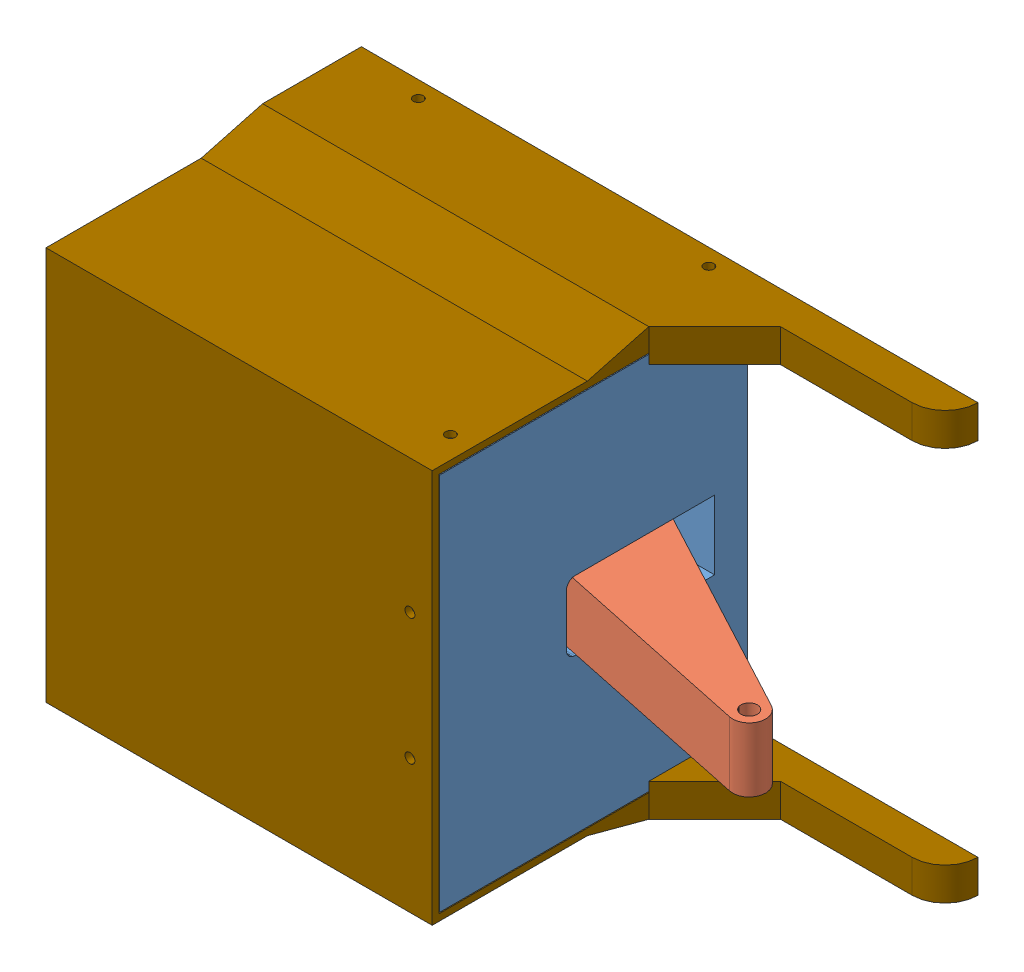
SolidWorks assembly v3, configuration Default. Lengths in mm.
Overall size (187.3 129.6 106.02).
11 component instances, 9 part files, 43 mates.
Components (placement in the parent):
- base-1: base [Default] at origin size (115 115 93.5)
- arm1-1: arm1 [Default] x (1 0 0) z (0 1 0) size (179.32 53.43 32)
- arm2-1: arm2 [Default] x (1 0 0) z (0 1 0) size (87.4 53.4 9.5)
- springBlock-1: springBlock [Default] at (-75 0 0) x (0 0 1) z (-1 0 0) size (83.5 115 40)
- SG90 - Micro Servo 9g - Tower Pro.1-1: SG90 - Micro Servo 9g - Tower Pro.1 [Peça] at (-32.2 15.85 24.85) x (1 0 0) z (0 -1 0) size (32.1 29.95 12.4)
- SG90 - Micro Servo 9g - Tower Pro.2-1: SG90 - Micro Servo 9g - Tower Pro.2 [Peça] at (-37.35 15.85 45.95) x (0.199094 0.97998 0) z (0.97998 -0.199094 0) size (19.5 3.8 6.9)
- servoArm-1: servoArm [Default] at (-37.35 15.85 45.95) x (0.199094 0.97998 0) z (0 0 1) size (31 12 6)
- arm1-2: arm1 [Default] at (-4.9003 0 3.2896) x (0.984808 0 -0.173648) z (0 1 0) size (179.32 53.43 32) (hidden)
- arm2-2: arm2 [Default] at (9.6437 0 -3.5384) x (0.953979 0 0.299873) z (0 1 0) size (87.4 53.4 9.5)
- potLink-1: potLink [Default] at (0 9.75 0) x (1 0 0) z (0 1 0) size (12 12 12)
- box-1: box [Default] x (-1 0 0) z (0 0 -1) size (187.3 129.6 95.8)
Mates (geometry in assembly coordinates):
- InPlace1: in place: plane of base-1 through (0 0 0) normal (0 0 1); moOrthogonalPlaneRef_w of base-1 through (0 0 0) normal (0 1 0); plane of base-1 through (0 0 0) normal (1 0 0); unknown of base-1
- Coincident1: coincident aligned: 
- Coincident2: coincident aligned: plane of base-1 through (0 0 0) normal (0 1 0)
- Coincident3: coincident anti-aligned: plane of base-1 through (0 0 0) normal (1 0 0)
- InPlace2: in place: plane of ? through (0 0 0) normal (0 1 0); plane of ? through (0 0 0) normal (0 0 -1); plane of ? through (0 0 0) normal (1 0 0); unknown of ?
- Coincident1: coincident aligned: 
- Coincident2: coincident aligned: plane of Part1^v3-1 through (0 0 0) normal (0 0 -1)
- Coincident3: coincident anti-aligned: plane of Part1^v3-1 through (0 0 0) normal (1 0 0)
- InPlace3: in place: plane of ? through (0 0 0) normal (0 1 0); plane of ? through (0 0 0) normal (0 0 -1); plane of ? through (0 0 0) normal (1 0 0); unknown of ?
- Coincident4: coincident aligned: 
- Coincident5: coincident aligned: plane of arm1-1 through (0 0 0) normal (0 0 -1)
- Coincident6: coincident anti-aligned: plane of arm1-1 through (0 0 0) normal (1 0 0)
- InPlace4: in place: plane of base-1 through (0 0 0) normal (0 1 0); plane of ? through (0 0 0) normal (0 1 0); plane of base-1 through (0 0 0) normal (0 1 0); plane of ? through (0 0 0) normal (0 0 -1); plane of base-1 through (0 0 0) normal (0 1 0); plane of ? through (0 0 0) normal (1 0 0); plane of base-1 through (0 0 0) normal (0 1 0); unknown of ?
- Coincident7: coincident aligned: plane of base-1; plane of arm2-1
- Coincident8: coincident aligned: moOrthogonalPlaneRef_w of base-1; plane of Part3^v3-1 through (0 0 0) normal (0 0 -1)
- Coincident9: coincident anti-aligned: moOrthogonalPlaneRef_w of base-1 through (24.2 -24.2 0) axis (0 0 -1); plane of Part3^v3-1 through (0 0 0) normal (1 0 0)
- InPlace5: in place: plane of base-1 through (-60 -40 10) normal (-1 0 0); plane of ? through (-60 0 0) normal (-1 0 0); plane of base-1 through (-60 -40 10) normal (-1 0 0); plane of ? through (-60 0 0) normal (0 1 0); plane of base-1 through (-60 -40 10) normal (-1 0 0); plane of ? through (-60 0 0) normal (0 0 1); plane of base-1 through (-75 -57.5 10) normal (-1 0 0); unknown of springBlock-1
- Coincident10: coincident aligned: plane of base-1 through (-75 -57.5 10) normal (-1 0 0); plane of springBlock-1 through (-75 0 0) normal (-1 0 0)
- Coincident11: coincident aligned: moOrthogonalPlaneRef_w of base-1 through (-75 0 0) normal (0 1 0); plane of springBlock-1 through (-75 0 0) normal (0 1 0)
- Coincident12: coincident anti-aligned: moOrthogonalPlaneRef_w of base-1 through (-75 0 0) normal (0 0 -1); plane of springBlock-1 through (-75 0 0) normal (0 0 1)
- Coincident13: coincident anti-aligned: plane of arm1-1 through (-14.65 22.25 30) normal (0 0 1); plane of SG90 - Micro Servo 9g - Tower Pro.1-1 through (-47.4 10.6 30) normal (0 0 -1)
- Coincident15: coincident anti-aligned: plane of arm1-1 through (100.9223 9.75 60.4318) normal (0 1 0); plane of SG90 - Micro Servo 9g - Tower Pro.1-1 through (-47.4 9.75 32.5) normal (0 -1 0)
- Distance1: distance = 0.3 mm anti-aligned: plane of SG90 - Micro Servo 9g - Tower Pro.1-1 through (-20.95 10.6 30) normal (1 0 0); plane of arm1-1 through (-20.65 22.25 30) normal (-1 0 0)
- Concentric1: concentric aligned: cylinder of SG90 - Micro Servo 9g - Tower Pro.1-1 through (-37.35 15.85 44.15) axis (0 0 1) radius 0.8; cylinder of SG90 - Micro Servo 9g - Tower Pro.2-1 through (-37.35 15.85 45.95) axis (0 0 1) radius 1.05
- Coincident17: coincident anti-aligned: plane of SG90 - Micro Servo 9g - Tower Pro.1-1 through (-37.35 15.85 44.15) normal (0 0 1); plane of SG90 - Micro Servo 9g - Tower Pro.2-1 through (-37.35 15.85 44.15) normal (0 0 -1)
- InPlace6: in place: plane of ? through (-37.7 15.85 45.95) normal (0 0 1); plane of ? through (0 0 45.95) normal (0 0 1); plane of ? through (-37.7 15.85 45.95) normal (0 0 1); plane of ? through (0 0 45.95) normal (0 1 0); plane of ? through (-37.7 15.85 45.95) normal (0 0 1); plane of ? through (0 0 45.95) normal (1 0 0); plane of SG90 - Micro Servo 9g - Tower Pro.2-1 through (-37.35 15.85 45.95) normal (0 0 1); unknown of servoArm-1
- Coincident18: coincident aligned: plane of SG90 - Micro Servo 9g - Tower Pro.2-1; plane of servoArm-1
- Coincident19: coincident aligned: moOrthogonalPlaneRef_w of SG90 - Micro Servo 9g - Tower Pro.2-1; plane of servoArm-1 through (-37.35 15.85 45.95) normal (-0.97998 0.199094 0)
- Coincident20: coincident anti-aligned: moOrthogonalPlaneRef_w of SG90 - Micro Servo 9g - Tower Pro.2-1; plane of servoArm-1 through (-37.35 15.85 45.95) normal (0.199094 0.97998 0)
- Concentric2: concentric aligned: cylinder of base-1 through (16.35 20 29.65) axis (0 -1 0) radius 9.65; cylinder of arm1-2 through (16.35 9.75 29.65) axis (0 -1 0) radius 3.1
- Coincident19: coincident aligned: plane of arm1-1 through (100.9223 9.75 60.4318) normal (0 1 0); plane of arm1-2 through (104.9827 9.75 45.2783) normal (0 1 0)
- Angle1: planar angle = 0.174533 rad aligned: plane of arm1-1 through (99.8896 9.75 65.324) normal (-0.206546 0 0.978437); plane of arm1-2 through (104.8152 9.75 50.2755) normal (-0.033504 0 0.999439)
- Concentric3: concentric anti-aligned: cylinder of base-1 through (16.35 -10.5 29.65) axis (0 -1 0) radius 7.65; cylinder of arm2-2 through (16.35 -4.75 29.65) axis (0 1 0) radius 9.65
- Coincident20: coincident aligned: plane of arm2-1 through (16.35 -4.75 29.65) normal (0 -1 0); plane of arm2-2 through (16.35 -4.75 29.65) normal (0 -1 0)
- Angle2: planar angle = 0.30456 rad aligned: plane of arm2-2 through (-56.7633 0 42.1505) normal (-0.299873 0 0.953979); plane of arm1-1 through (-57.2518 -2.9719 63.5) normal (0 0 1)
- InPlace8: in place: plane of ? through (100.9223 9.75 60.4318) normal (0 1 0); plane of potLink-1 through (0 9.75 0) normal (0 1 0); plane of ? through (100.9223 9.75 60.4318) normal (0 1 0); plane of potLink-1 through (0 9.75 0) normal (0 0 -1); plane of ? through (100.9223 9.75 60.4318) normal (0 1 0); plane of potLink-1 through (0 9.75 0) normal (1 0 0); plane of ? through (100.9223 9.75 60.4318) normal (0 1 0); unknown of potLink-1
- Coincident24: coincident aligned: plane of arm1-1; plane of potLink-1
- Coincident25: coincident aligned: moOrthogonalPlaneRef_w of arm1-1 through (0 9.75 0) normal (0 0 -1); plane of Part2^v3-1 through (0 9.75 0) normal (0 0 -1)
- Coincident26: coincident anti-aligned: moOrthogonalPlaneRef_w of arm1-1 through (0 9.75 0) normal (-1 0 0); plane of Part2^v3-1 through (0 9.75 0) normal (1 0 0)
- InPlace9: in place: plane of base-1 through (0 0 0) normal (0 0 -1); plane of box-1 through (0 0 0) normal (0 0 -1); plane of base-1 through (0 0 0) normal (0 0 -1); plane of box-1 through (0 0 0) normal (0 1 0); plane of base-1 through (0 0 0) normal (0 0 -1); plane of box-1 through (0 0 0) normal (-1 0 0); plane of base-1 through (0 0 0) normal (0 0 -1); unknown of box-1
- Coincident21: coincident aligned: plane of base-1; plane of box-1
- Coincident22: coincident aligned: moOrthogonalPlaneRef_w of base-1 through (0 0 0) normal (0 1 0); plane of box-1 through (0 0 0) normal (0 1 0)
- Coincident23: coincident anti-aligned: moOrthogonalPlaneRef_w of base-1 through (0 0 0) normal (1 0 0); plane of box-1 through (0 0 0) normal (-1 0 0)
